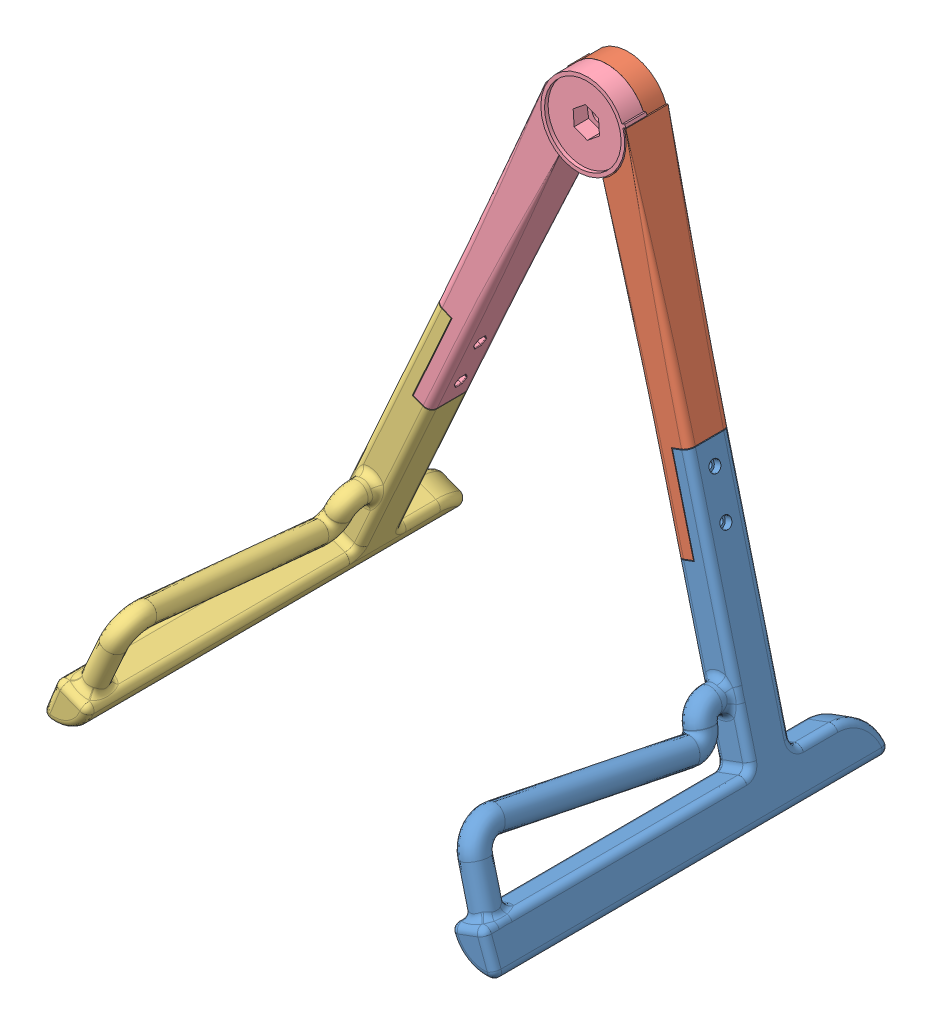
SolidWorks assembly Assembly, configuration Default. Lengths in mm.
Overall size (321.79 383.98 281.02).
5 component instances, 5 part files, 12 mates.
Components (placement in the parent):
- right_section_bottom-1: right_section_bottom [Default] at (24.7036 3.932 -55.589) x (0.938712 0.344692 -0.002677) z (0.003182 -0.000898 0.999995) size (25 200 280)
- right_section_top-1: right_section_top [Default] at (-32.6725 196.4532 -55.2773) x (-0.938712 -0.344692 0.002677) z (-0.003182 0.000898 -0.999995) size (58.8 259.94 50.38)
- left_section_bottom-1: left_section_bottom [Default] at (-272.7308 16.9352 -54.6309) x (0.928939 -0.370218 -0.003288) z (0.003182 -0.000898 0.999995) size (25 200 280)
- left_section_top-1: left_section_top [Default] at (-186.8904 198.5609 -54.7847) x (-0.928939 0.370218 0.003288) z (-0.003182 0.000898 -0.999995) size (58.78 259.92 50.39)
- nut_holder-1: nut_holder [Default] at (-108.0181 350.0934 -155.9001) x (0.000001 1 0.000898) z (-0.999995 -0.000001 0.003182) size (22 11.13 22)
Mates (geometry in assembly coordinates):
- Coincident19: coincident: plane of right_section_top-1 through (-107.9991 350.088 -149.9001) normal (0.003182 -0.000898 0.999995); plane of left_section_top-1 through (-107.9991 350.088 -149.9001) normal (-0.003182 0.000898 -0.999995)
- Coincident23: coincident: circle of right_section_top-1; circle of left_section_top-1
- Concentric1: concentric: circle of right_section_top-1; circle of nut_holder-1
- Coincident24: coincident: plane of right_section_top-1 through (-108.0181 350.0934 -155.9001) normal (-0.003182 0.000898 -0.999995); plane of nut_holder-1 through (-108.0181 350.0934 -155.9001) normal (0.003182 -0.000898 0.999995)
- Concentric3: concentric: cylinder of left_section_bottom-1 through (-186.5903 182.2648 -133.6153) axis (-0.928939 0.370218 0.003288) radius 2.5; cylinder of left_section_top-1 through (-204.3062 189.3253 -133.5526) axis (0.928939 -0.370218 -0.003288) radius 2.375
- Coincident29: coincident: plane of left_section_bottom-1 through (-12.4377 128.4615 -150.4864) normal (-0.035436 -0.080068 -0.996159); plane of left_section_top-1 through (-198.8048 203.2741 -149.87) normal (-0.035436 -0.080068 -0.996159)
- Coincident30: coincident: plane of left_section_bottom-1 through (-272.2853 16.8095 85.3683) normal (-0.928939 0.370218 0.003288); plane of left_section_top-1 through (-198.5021 203.1887 -54.7436) normal (-0.928939 0.370218 0.003288)
- Concentric4: concentric: cylinder of left_section_bottom-1 through (-197.604 154.6062 -131.0004) axis (-0.928939 0.370218 0.003288) radius 2.5; cylinder of left_section_top-1 through (-215.3199 161.6667 -130.9377) axis (0.928939 -0.370218 -0.003288) radius 2.375
- Concentric2: concentric: cylinder of right_section_bottom-1 through (-39.4868 178.1346 -134.0871) axis (0.938712 0.344692 -0.002677) radius 2.5; cylinder of right_section_top-1 through (-21.4471 184.7587 -134.1385) axis (-0.938712 -0.344692 0.002677) radius 2.375
- Coincident33: coincident: plane of right_section_bottom-1 through (143.9781 260.9824 -150.8651) normal (0.026872 -0.08092 -0.996358); plane of right_section_top-1 through (-44.7091 192.23 -150.3702) normal (0.026872 -0.08092 -0.996358)
- Coincident31: coincident: plane of right_section_bottom-1 through (48.6168 12.4236 84.3433) normal (0.938712 0.344692 -0.002677); plane of right_section_top-1 through (-20.9386 200.7618 -55.3107) normal (0.938712 0.344692 -0.002677)
- Concentric5: concentric: cylinder of right_section_bottom-1 through (-29.2166 150.1851 -131.5402) axis (0.938712 0.344692 -0.002677) radius 2.5; cylinder of right_section_top-1 through (-11.1769 156.8092 -131.5916) axis (-0.938712 -0.344692 0.002677) radius 2.375
